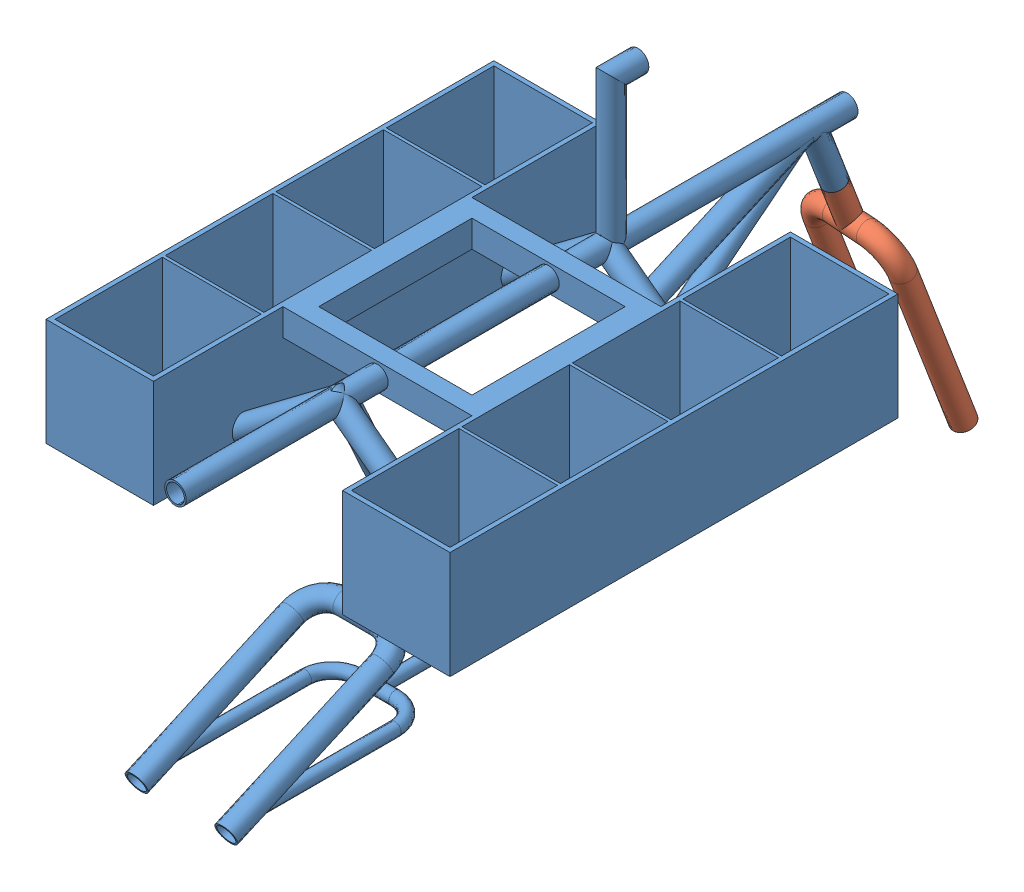
SolidWorks assembly DB_assembly1, configuration Default. Lengths in mm.
Overall size (796.53 1592.51 1282.47).
2 component instances, 2 part files, 3 mates.
Components (placement in the parent):
- model1-2: model1 [Default] at origin size (796.53 1589.76 1100)
- frontWheel_fork-2: frontWheel_fork [Default] at (-14.5477 0.1418 -0.3711) x (0.050974 -0.000497 -0.9987) z (0.99851 -0.019473 0.050974) size (1277.02 1589.76 124)
Mates (geometry in assembly coordinates):
- Concentric4: concentric aligned: cylinder of model1-2 through (0 0 -285.3937) axis (0 -0.934155 -0.356867) radius 12; cylinder of frontWheel_fork-2 through (0 -65.3909 -310.3743) axis (0 -0.934155 -0.356867) radius 12
- Coincident2: coincident anti-aligned: plane of model1-2 through (0 -65.3909 -310.3743) normal (0 -0.934155 -0.356867); plane of frontWheel_fork-2 through (0 -65.3909 -310.3743) normal (0 0.934155 0.356867)
- Angle2: planar angle = 0 rad: cylinder of frontWheel_fork-2 through (0 -65.3909 -310.3743) axis (0 -0.934155 -0.356867) radius 12; cylinder of model1-2 through (0 0 -285.3937) axis (0 -0.934155 -0.356867) radius 12
